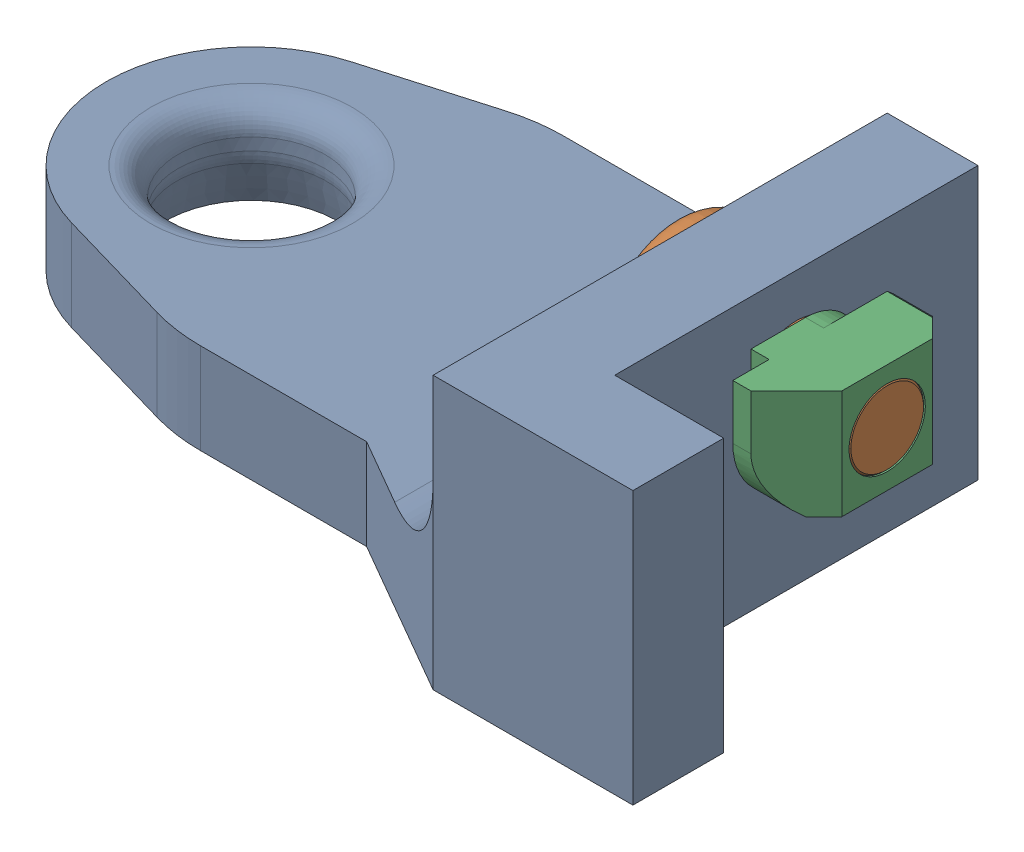
SolidWorks assembly front_right_leadscrew_retainer_assembly, configuration Default. Lengths in mm.
Overall size (44 15 25).
3 component instances, 3 part files, 0 mates.
Components (placement in the parent):
- compact_front_leadscrew_retainer_Front Right Leadscrew Retainer-1: compact_front_leadscrew_retainer_Front Right Leadscrew Retainer [Default] at (304.071 324.0105 414.2083) x (0 0 1) z (-1 0 0) size (25 15 44)
- m5_low_profile_screw_template_M5 x 10-1: m5_low_profile_screw_template_M5 x 10 [Default] at (339.071 334.0105 434.2083) size (11.62 9 9)
- m5_locking_t_nut_20x20_generic-1: m5_locking_t_nut_20x20_generic [Default] at (339.071 331.0105 434.2083) x (0 0 -1) z (0 1 0) size (10 4.5 6)
